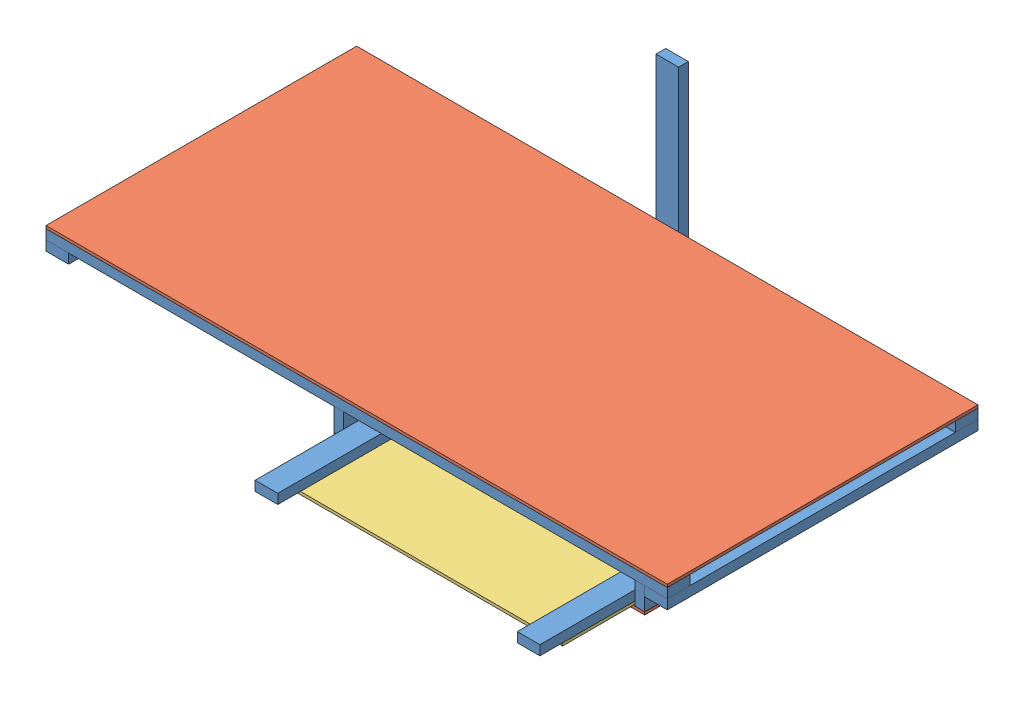
SolidWorks assembly LaserCutter, configuration Default. Lengths in mm.
Overall size (2438.4 709.61 1623.82).
14 component instances, 4 part files, 26 mates.
Components (placement in the parent):
- 2x4-1: 2x4 [4ft] at (-97.1386 -55.8116 -556.8217) size (88.9 38.1 1219.2)
- 2x4-2: 2x4 [8ft] at (2341.2614 -17.7116 -556.8217) x (0 0 1) z (-1 0 0) size (88.9 38.1 2438.4)
- 2x4-3: 2x4 [4ft] at (2252.3614 -55.8116 -556.8217) size (88.9 38.1 1219.2)
- 2x4-4: 2x4 [8ft] at (-97.1386 -17.7116 662.3783) x (0 0 -1) z (1 0 0) size (88.9 38.1 2438.4)
- Plywood-1: Plywood [4ftX8ft] at (2341.2614 31.5009 -556.8217) x (0 0 1) z (0 -1 0) size (1219.2 2438.4 11.11)
- 2x4-6: 2x4 [2ft] at (1077.6114 -17.7116 -556.8217) x (1 0 0) z (0 1 0) size (88.9 38.1 609.6)
- 2x4-7: 2x4 [4ft] at (2214.2614 -17.7116 -556.8217) x (0 -1 0) z (0 0 1) size (88.9 38.1 1219.2)
- Plywood-2: Plywood [4ftX4ft] at (1033.1614 -106.6116 -556.8217) x (1 0 0) z (0 -1 0) size (1219.2 1219.2 11.11)
- Tray-1: Tray [Default] at (1642.6055 -131.1934 765.8605) x (0 0 1) z (0 1 0) size (698.5 1117.6 49.21)
  - Plywood_LaserCutter-1: Plywood_LaserCutter [Tray] at (-435.4588 -552.4767 24.5819) size (609.6 1117.6 11.11)
  - 2x4_LaserCutter-1: 2x4_LaserCutter [TrayWidth] at (-435.4588 565.1233 35.6944) x (1 0 0) z (0 -1 0) size (88.9 38.1 1117.6)
  - 2x4-2: 2x4 [2ft] at (263.0412 -463.5767 35.6944) x (0 -1 0) z (-1 0 0) size (88.9 38.1 609.6)
  - 2x4-3: 2x4 [2ft] at (-346.5588 476.2233 35.6944) x (0 1 0) z (1 0 0) size (88.9 38.1 609.6)
- 2x4-9: 2x4 [4ft] at (1033.1614 -17.7116 -556.8217) x (0 -1 0) z (0 0 1) size (88.9 38.1 1219.2)
Mates (geometry in assembly coordinates):
- Coincident1: coincident anti-aligned: plane of 2x4-1 through (-97.1386 -17.7116 662.3783) normal (0 1 0); plane of 2x4-2 through (-97.1386 -17.7116 -556.8217) normal (0 -1 0)
- Coincident2: coincident aligned: plane of 2x4-1 through (-97.1386 -55.8116 -556.8217) normal (0 0 -1); plane of 2x4-2 through (-97.1386 -17.7116 -556.8217) normal (0 0 -1)
- Coincident3: coincident aligned: plane of 2x4-1 through (-97.1386 -55.8116 662.3783) normal (-1 0 0); plane of 2x4-2 through (-97.1386 -17.7116 -556.8217) normal (-1 0 0)
- Coincident4: coincident anti-aligned: plane of 2x4-2 through (-97.1386 -17.7116 -556.8217) normal (0 -1 0); plane of 2x4-3 through (2252.3614 -17.7116 662.3783) normal (0 1 0)
- Coincident5: coincident aligned: plane of 2x4-2 through (-97.1386 -17.7116 -556.8217) normal (0 0 -1); plane of 2x4-3 through (2252.3614 -55.8116 -556.8217) normal (0 0 -1)
- Coincident6: coincident aligned: plane of 2x4-2 through (2341.2614 -17.7116 -556.8217) normal (1 0 0); plane of 2x4-3 through (2341.2614 -55.8116 662.3783) normal (1 0 0)
- Coincident7: coincident aligned: plane of 2x4-1 through (-97.1386 -55.8116 662.3783) normal (0 0 1); plane of 2x4-4 through (2341.2614 -17.7116 662.3783) normal (0 0 1)
- Coincident8: coincident aligned: plane of 2x4-1 through (-97.1386 -55.8116 662.3783) normal (-1 0 0); plane of 2x4-4 through (-97.1386 -17.7116 662.3783) normal (-1 0 0)
- Coincident9: coincident aligned: plane of 2x4-1 through (-97.1386 -55.8116 662.3783) normal (0 0 1); plane of 2x4-4 through (2341.2614 -17.7116 662.3783) normal (0 0 1)
- Coincident10: coincident anti-aligned: plane of 2x4-1 through (-97.1386 -17.7116 662.3783) normal (0 1 0); plane of 2x4-4 through (2341.2614 -17.7116 662.3783) normal (0 -1 0)
- Coincident13: coincident anti-aligned: plane of 2x4-4 through (2341.2614 20.3884 662.3783) normal (0 1 0); plane of Plywood-1 through (2341.2614 20.3884 -556.8217) normal (0 -1 0)
- Coincident14: coincident aligned: plane of 2x4-4 through (2341.2614 -17.7116 662.3783) normal (0 0 1); plane of Plywood-1 through (2341.2614 20.3884 662.3783) normal (0 0 1)
- Coincident15: coincident aligned: plane of 2x4-4 through (2341.2614 -17.7116 662.3783) normal (1 0 0); plane of Plywood-1 through (2341.2614 20.3884 -556.8217) normal (1 0 0)
- Coincident19: coincident anti-aligned: plane of 2x4-4 through (2341.2614 -17.7116 662.3783) normal (0 -1 0); plane of 2x4-7 through (2214.2614 -17.7116 662.3783) normal (0 1 0)
- Coincident20: coincident aligned: plane of 2x4-2 through (-97.1386 -17.7116 -556.8217) normal (0 0 -1); plane of 2x4-7 through (2214.2614 -17.7116 -556.8217) normal (0 0 -1)
- Coincident23: coincident aligned: plane of 2x4-7 through (2252.3614 -17.7116 662.3783) normal (1 0 0); plane of Plywood-2 through (2252.3614 -117.7241 -556.8217) normal (1 0 0)
- Coincident25: coincident aligned: plane of 2x4-7 through (2214.2614 -17.7116 -556.8217) normal (0 0 -1); plane of Plywood-2 through (1033.1614 -117.7241 -556.8217) normal (0 0 -1)
- Coincident26: coincident anti-aligned: plane of Plywood-2 through (1033.1614 -106.6116 -556.8217) normal (0 1 0); plane of Tray-1/Plywood_LaserCutter-1 through (1090.1288 -106.6116 330.4017) normal (0 -1 0)
- Coincident27: coincident anti-aligned: plane of 2x4-2 through (-97.1386 -17.7116 -556.8217) normal (0 0 -1); plane of 2x4-6 through (1077.6114 591.8884 -556.8217) normal (0 0 1)
- Coincident28: coincident aligned: plane of 2x4-2 through (-97.1386 -17.7116 -556.8217) normal (0 -1 0); plane of 2x4-6 through (1077.6114 -17.7116 -556.8217) normal (0 -1 0)
- Coincident30: coincident: moEndPointRef_w of 2x4-6; plane of assembly
- Coincident31: coincident anti-aligned: plane of 2x4-3 through (2252.3614 -55.8116 662.3783) normal (-1 0 0); plane of 2x4-7 through (2252.3614 -17.7116 662.3783) normal (1 0 0)
- Coincident32: coincident anti-aligned: plane of 2x4-7 through (2214.2614 -106.6116 662.3783) normal (0 -1 0); plane of Plywood-2 through (1033.1614 -106.6116 -556.8217) normal (0 1 0)
- Coincident33: coincident anti-aligned: plane of 2x4-4 through (2341.2614 -17.7116 662.3783) normal (0 -1 0); plane of 2x4-9 through (1033.1614 -17.7116 662.3783) normal (0 1 0)
- Coincident34: coincident aligned: plane of 2x4-7 through (2214.2614 -17.7116 -556.8217) normal (0 0 -1); plane of 2x4-9 through (1033.1614 -17.7116 -556.8217) normal (0 0 -1)
- Coincident35: coincident aligned: plane of Plywood-2 through (1033.1614 -117.7241 -556.8217) normal (-1 0 0); plane of 2x4-9 through (1033.1614 -17.7116 662.3783) normal (-1 0 0)
